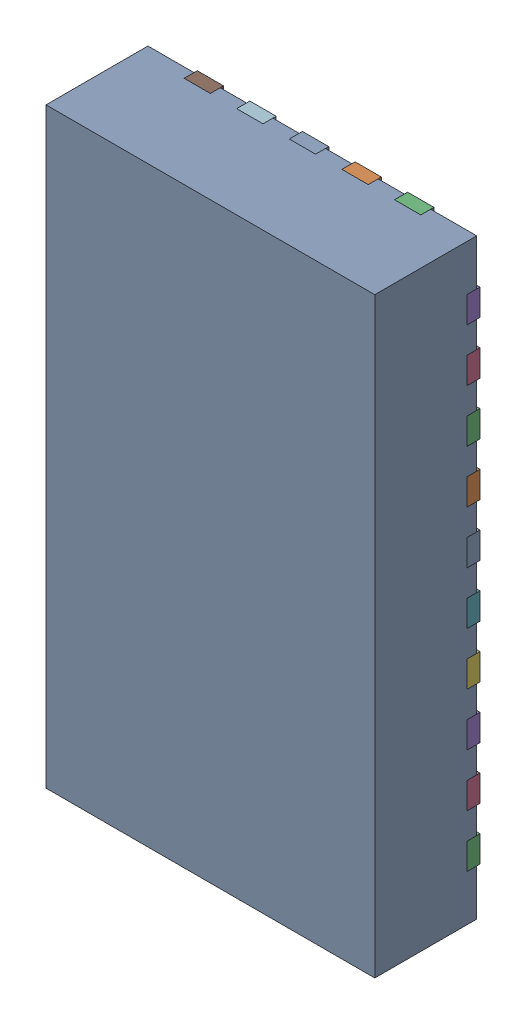
SolidWorks assembly RNH0030A, configuration Défaut. Lengths in mm.
Overall size (2.5 4.5 0.8).
33 component instances, 32 part files, 0 mates.
Components (placement in the parent):
- BODY-QFN-1: BODY-QFN [Défaut] at (0 0 0.025) x (1 0 0) z (0 -1 0) size (2.5 0.78 4.5)
- FRAME-RNH0030A-1: FRAME-RNH0030A [Défaut] x (1 0 0) z (0 -1 0) size (2.5 0.2 4.5)
  - Open CASCADE STEP translator 7.5 2.204.1.2.1-1: Open CASCADE STEP translator 7.5 2.204.1.2.1 [Défaut] at origin size (1.4 0.2 3.4)
  - Open CASCADE STEP translator 7.5 2.204.1.2.2-1: Open CASCADE STEP translator 7.5 2.204.1.2.2 [Défaut] at origin size (0.3 0.1 0.2)
  - Open CASCADE STEP translator 7.5 2.204.1.2.3-1: Open CASCADE STEP translator 7.5 2.204.1.2.3 [Défaut] at origin size (0.3 0.1 0.2)
  - Open CASCADE STEP translator 7.5 2.204.1.2.4-1: Open CASCADE STEP translator 7.5 2.204.1.2.4 [Défaut] at origin size (0.3 0.1 0.2)
  - Open CASCADE STEP translator 7.5 2.204.1.2.5-1: Open CASCADE STEP translator 7.5 2.204.1.2.5 [Défaut] at origin size (0.3 0.1 0.2)
  - Open CASCADE STEP translator 7.5 2.204.1.2.6-1: Open CASCADE STEP translator 7.5 2.204.1.2.6 [Défaut] at origin size (0.3 0.1 0.2)
  - Open CASCADE STEP translator 7.5 2.204.1.2.7-1: Open CASCADE STEP translator 7.5 2.204.1.2.7 [Défaut] at origin size (0.3 0.1 0.2)
  - Open CASCADE STEP translator 7.5 2.204.1.2.8-1: Open CASCADE STEP translator 7.5 2.204.1.2.8 [Défaut] at origin size (0.3 0.1 0.2)
  - Open CASCADE STEP translator 7.5 2.204.1.2.9-1: Open CASCADE STEP translator 7.5 2.204.1.2.9 [Défaut] at origin size (0.3 0.1 0.2)
  - Open CASCADE STEP translator 7.5 2.204.1.2.10-1: Open CASCADE STEP translator 7.5 2.204.1.2.10 [Défaut] at origin size (0.3 0.1 0.2)
  - Open CASCADE STEP translator 7.5 2.204.1.2.11-1: Open CASCADE STEP translator 7.5 2.204.1.2.11 [Défaut] at origin size (0.3 0.1 0.2)
  - Open CASCADE STEP translator 7.5 2.204.1.2.12-1: Open CASCADE STEP translator 7.5 2.204.1.2.12 [Défaut] at origin size (0.3 0.1 0.2)
  - Open CASCADE STEP translator 7.5 2.204.1.2.13-1: Open CASCADE STEP translator 7.5 2.204.1.2.13 [Défaut] at origin size (0.3 0.1 0.2)
  - Open CASCADE STEP translator 7.5 2.204.1.2.14-1: Open CASCADE STEP translator 7.5 2.204.1.2.14 [Défaut] at origin size (0.3 0.1 0.2)
  - Open CASCADE STEP translator 7.5 2.204.1.2.15-1: Open CASCADE STEP translator 7.5 2.204.1.2.15 [Défaut] at origin size (0.3 0.1 0.2)
  - Open CASCADE STEP translator 7.5 2.204.1.2.16-1: Open CASCADE STEP translator 7.5 2.204.1.2.16 [Défaut] at origin size (0.3 0.1 0.2)
  - Open CASCADE STEP translator 7.5 2.204.1.2.17-1: Open CASCADE STEP translator 7.5 2.204.1.2.17 [Défaut] at origin size (0.3 0.1 0.2)
  - Open CASCADE STEP translator 7.5 2.204.1.2.18-1: Open CASCADE STEP translator 7.5 2.204.1.2.18 [Défaut] at origin size (0.3 0.1 0.2)
  - Open CASCADE STEP translator 7.5 2.204.1.2.19-1: Open CASCADE STEP translator 7.5 2.204.1.2.19 [Défaut] at origin size (0.3 0.1 0.2)
  - Open CASCADE STEP translator 7.5 2.204.1.2.20-1: Open CASCADE STEP translator 7.5 2.204.1.2.20 [Défaut] at origin size (0.3 0.1 0.2)
  - Open CASCADE STEP translator 7.5 2.204.1.2.21-1: Open CASCADE STEP translator 7.5 2.204.1.2.21 [Défaut] at origin size (0.3 0.1 0.2)
  - Open CASCADE STEP translator 7.5 2.204.1.2.22-1: Open CASCADE STEP translator 7.5 2.204.1.2.22 [Défaut] at origin size (0.2 0.1 0.3)
  - Open CASCADE STEP translator 7.5 2.204.1.2.23-1: Open CASCADE STEP translator 7.5 2.204.1.2.23 [Défaut] at origin size (0.2 0.1 0.3)
  - Open CASCADE STEP translator 7.5 2.204.1.2.24-1: Open CASCADE STEP translator 7.5 2.204.1.2.24 [Défaut] at origin size (0.2 0.1 0.3)
  - Open CASCADE STEP translator 7.5 2.204.1.2.25-1: Open CASCADE STEP translator 7.5 2.204.1.2.25 [Défaut] at origin size (0.2 0.1 0.3)
  - Open CASCADE STEP translator 7.5 2.204.1.2.26-1: Open CASCADE STEP translator 7.5 2.204.1.2.26 [Défaut] at origin size (0.2 0.1 0.3)
  - Open CASCADE STEP translator 7.5 2.204.1.2.27-1: Open CASCADE STEP translator 7.5 2.204.1.2.27 [Défaut] at origin size (0.2 0.1 0.3)
  - Open CASCADE STEP translator 7.5 2.204.1.2.28-1: Open CASCADE STEP translator 7.5 2.204.1.2.28 [Défaut] at origin size (0.2 0.1 0.3)
  - Open CASCADE STEP translator 7.5 2.204.1.2.29-1: Open CASCADE STEP translator 7.5 2.204.1.2.29 [Défaut] at origin size (0.2 0.1 0.3)
  - Open CASCADE STEP translator 7.5 2.204.1.2.30-1: Open CASCADE STEP translator 7.5 2.204.1.2.30 [Défaut] at origin size (0.2 0.1 0.3)
  - Open CASCADE STEP translator 7.5 2.204.1.2.31-1: Open CASCADE STEP translator 7.5 2.204.1.2.31 [Défaut] at origin size (0.2 0.1 0.3)
